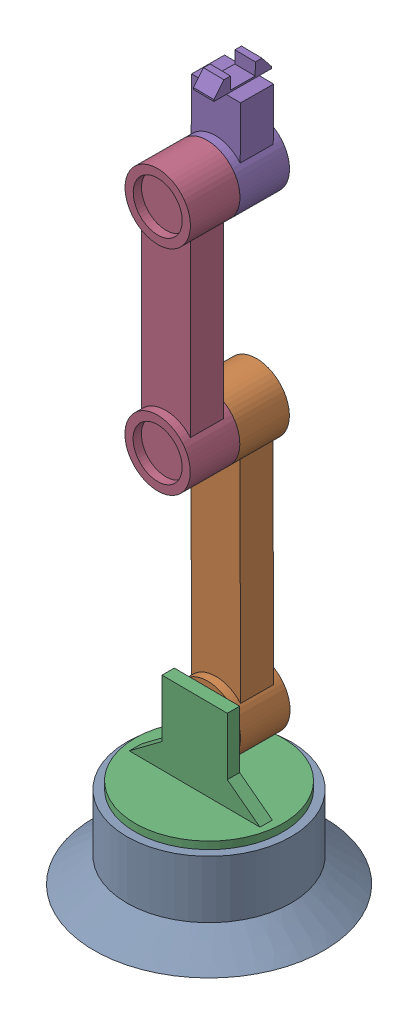
SolidWorks assembly Robotic_arm_assembly, configuration Default. Lengths in mm.
Overall size (280 852.14 280).
5 component instances, 5 part files, 8 mates.
Components (placement in the parent):
- Base-1: Base [Default] at (58.2751 87.298 241.9211) size (280 110 280)
- Shoulder-1: Shoulder [Default] at (58.267 262.0269 243.421) x (0.005424 0 -0.999985) z (-0.002631 0.999997 -0.000014) size (70 80 389.98)
- Base_Holder-1: Base_Holder [Default] at (58.1802 246.298 259.4208) x (0.005424 0 -0.999985) z (0.999985 0 0.005424) size (180 120 180)
- Elbow-1: Elbow [Default] at (57.4515 572.0042 243.4166) x (0.000582 1 0.000003) z (-0.005424 0 0.999985) size (340 80 70)
- Wrist_1-1: Wrist_1 [Default] at (57.6028 832.0042 243.4174) x (0.005424 0 -0.999985) z (-0.007546 -0.999972 -0.000041) size (70 80 147.13)
Mates (geometry in assembly coordinates):
- Concentric1: concentric anti-aligned: cylinder of Base-1 through (58.2751 197.298 241.9211) axis (0 -1 0) radius 5; cylinder of Base_Holder-1 through (58.2751 176.298 241.9211) axis (0 1 0) radius 5
- Distance1: distance = 21 mm anti-aligned: plane of Base_Holder-1 through (58.2751 176.298 241.9211) normal (0 -1 0); plane of Base-1 through (58.2751 197.298 241.9211) normal (0 1 0)
- Concentric2: concentric aligned: circle of Shoulder-1; cylinder of Base_Holder-1 through (58.3158 262.0269 234.4212) axis (-0.005424 0 0.999985) radius 6
- Distance2: distance = 1 mm anti-aligned: plane of Shoulder-1 through (58.267 262.0269 243.421) normal (-0.005424 0 0.999985); plane of Base_Holder-1 through (58.2616 246.298 244.421) normal (0.005424 0 -0.999985)
- Concentric3: concentric aligned: cylinder of Shoulder-1 through (57.3973 572.0042 253.4165) axis (0.005424 0 -0.999985) radius 6; cylinder of Elbow-1 through (57.3973 572.0042 253.4165) axis (0.005424 0 -0.999985) radius 6
- Distance3: distance = 50 mm aligned: plane of Elbow-1 through (27.3553 872.0226 293.2541) normal (-0.005424 0 0.999985); plane of Shoulder-1 through (57.4515 572.0042 243.4166) normal (-0.005424 0 0.999985)
- Concentric5: concentric aligned: cylinder of Elbow-1 through (57.657 832.0042 233.4176) axis (-0.005424 0 0.999985) radius 6; cylinder of Wrist_1-1 through (57.6353 832.0042 237.4175) axis (-0.005424 0 0.999985) radius 6
- Distance5: distance = 0 mm anti-aligned: plane of Wrist_1-1 through (57.6028 832.0042 243.4174) normal (-0.005424 0 0.999985); plane of Elbow-1 through (57.6028 832.0042 243.4174) normal (0.005424 0 -0.999985)
